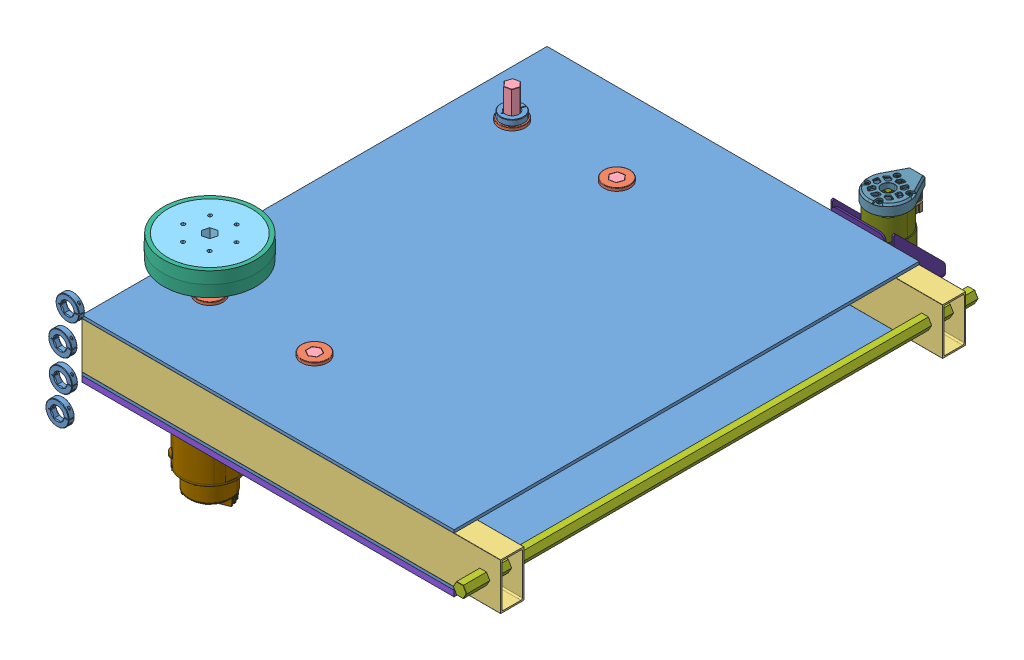
SolidWorks assembly ShooterAssem4, configuration Default. Lengths in mm.
Overall size (478.25 250.86 599.98).
87 component instances, 21 part files, 96 mates.
Components (placement in the parent):
- ShooterPlate-1: ShooterPlate [Default] at origin size (406.4 3.17 508)
- am-2986 FR8ZZ Hex Bearing.step-1: am-2986 FR8ZZ Hex Bearing.step [Default] at (50.8 6.4033 -88.9) x (0.268339 0 -0.963324) z (0 -1 0) size (31.12 31.12 7.93)
- am-2986 FR8ZZ Hex Bearing.step-2: am-2986 FR8ZZ Hex Bearing.step [Default] at (50.8 6.4033 -419.1) x (0.978513 0 -0.206187) z (0 -1 0) size (31.12 31.12 7.93)
- am-2986 FR8ZZ Hex Bearing.step-3: am-2986 FR8ZZ Hex Bearing.step [Default] at (165.1 6.4033 -419.1) x (0.331233 0 -0.943549) z (0 -1 0) size (31.12 31.12 7.93)
- am-2986 FR8ZZ Hex Bearing.step-4: am-2986 FR8ZZ Hex Bearing.step [Default] at (165.1 6.4033 -88.9) x (0.016765 0 0.999859) z (0 -1 0) size (31.12 31.12 7.93)
- side-4: side [Default] at (457.2 -25.4 -495.3) x (0 0 1) z (-1 0 0) size (25.4 50.8 457.2)
- side-5: side [Default] at (457.2 -25.4 -12.7) x (0 0 1) z (-1 0 0) size (25.4 50.8 457.2)
- 4in hex shaft-1: 4in hex shaft [Default] at (165.1 -95.1967 -88.9) x (0.874286 0 0.485411) z (0 1 0) size (14.66 12.7 101.6)
- 4in hex shaft-2: 4in hex shaft [Default] at (165.1 6.4033 -419.1) x (0.331233 0 -0.943549) z (0 -1 0) size (14.66 12.7 101.6)
- 4in hex shaft-3: 4in hex shaft [Default] at (50.8 39.1882 -88.9) x (0.268339 0 -0.963324) z (0 -1 0) size (14.66 12.7 101.6)
- 4in hex shaft-4: 4in hex shaft [Default] at (50.8 -64.1161 -419.1) x (0.978513 0 -0.206187) z (0 1 0) size (14.66 12.7 101.6)
- am-2647 4inWheel 500 Hex REV2-1: am-2647 4inWheel 500 Hex REV2 [Default] at (165.0712 -29.2956 -419.0946) x (0 -1 0) z (-0.331233 0 0.943549) size (25.4 101.6 101.6)
  - am-2647 4inWheel 500 Hex REV2.STEP-1: am-2647 4inWheel 500 Hex REV2.STEP [Default] at origin size (25.4 101.6 101.6)
    - 4in Wheel Intergreated Hub 500 HEX.STEP-1: 4in Wheel Intergreated Hub 500 HEX.STEP [Default] at origin size (25.4 92.71 92.71)
    - 4in Tread.STEP-1: 4in Tread.STEP [Default] at origin size (25.4 101.6 101.6)
- am-2647 4inWheel 500 Hex REV2-5: am-2647 4inWheel 500 Hex REV2 [Default] at (165.0739 -35.2807 -88.9436) x (0 -1 0) z (0.874286 0 0.485411) size (25.4 101.6 101.6)
  - am-2647 4inWheel 500 Hex REV2.STEP-1: am-2647 4inWheel 500 Hex REV2.STEP [Default] at origin size (25.4 101.6 101.6)
    - 4in Wheel Intergreated Hub 500 HEX.STEP-1: 4in Wheel Intergreated Hub 500 HEX.STEP [Default] at origin size (25.4 92.71 92.71)
    - 4in Tread.STEP-1: 4in Tread.STEP [Default] at origin size (25.4 101.6 101.6)
- am-2647 4inWheel 500 Hex REV2-6: am-2647 4inWheel 500 Hex REV2 [Default] at (50.7804 -22.6519 -419.1218) x (0 1 0) z (0.310693 0 -0.95051) size (25.4 101.6 101.6)
  - am-2647 4inWheel 500 Hex REV2.STEP-1: am-2647 4inWheel 500 Hex REV2.STEP [Default] at origin size (25.4 101.6 101.6)
    - 4in Wheel Intergreated Hub 500 HEX.STEP-1: 4in Wheel Intergreated Hub 500 HEX.STEP [Default] at origin size (25.4 92.71 92.71)
    - 4in Tread.STEP-1: 4in Tread.STEP [Default] at origin size (25.4 101.6 101.6)
- am-2647 4inWheel 500 Hex REV2-7: am-2647 4inWheel 500 Hex REV2 [Default] at (50.7921 47.535 -88.8717) x (0 -1 0) z (0.700094 0 0.714051) size (25.4 101.6 101.6)
  - am-2647 4inWheel 500 Hex REV2.STEP-1: am-2647 4inWheel 500 Hex REV2.STEP [Default] at origin size (25.4 101.6 101.6)
    - 4in Wheel Intergreated Hub 500 HEX.STEP-1: 4in Wheel Intergreated Hub 500 HEX.STEP [Default] at origin size (25.4 92.71 92.71)
    - 4in Tread.STEP-1: 4in Tread.STEP [Default] at origin size (25.4 101.6 101.6)
- am-2986 FR8ZZ Hex Bearing.step-5: am-2986 FR8ZZ Hex Bearing.step [Default] at (165.1 -57.2033 -88.9) x (0.874286 0 0.485411) z (0 1 0) size (31.12 31.12 7.93)
- am-2986 FR8ZZ Hex Bearing.step-7: am-2986 FR8ZZ Hex Bearing.step [Default] at (165.1 -57.2033 -419.1) x (-0.651521 0 -0.758631) z (0 1 0) size (31.12 31.12 7.93)
- am-2986 FR8ZZ Hex Bearing.step-8: am-2986 FR8ZZ Hex Bearing.step [Default] at (50.8 -57.2033 -419.1) x (0.667819 0 0.744323) z (0 1 0) size (31.12 31.12 7.93)
- am-2986 FR8ZZ Hex Bearing.step-9: am-2986 FR8ZZ Hex Bearing.step [Default] at (50.8 -47.5717 -88.9) x (-0.968433 0 0.249274) z (0 -1 0) size (31.12 31.12 7.93)
- ShooterPlate-2: ShooterPlate [Default] at (0 -53.975 0) size (406.4 3.17 508)
- shooteraxle-1: shooteraxle [Default] at (438.15 -25.4 -533.4) size (14.66 12.7 558.8)
- ThickStick-1: ThickStick [Default] at (0 -60.325 -482.6) size (406.4 6.35 25.4)
- ThickStick-2: ThickStick [Default] at (0 -60.325 0) size (406.4 6.35 25.4)
- Falcon 500.step-2: Falcon 500.step [Default] at (50.8431 -160.0533 -419.2317) x (0.853787 0 -0.520622) z (0 1 0) size (62.05 60 125.3)
- Falcon 500.step-3: Falcon 500.step [Default] at (50.7628 -158.349 -88.7665) x (-0.623742 0 0.78163) z (0 1 0) size (62.05 60 125.3)
- 775pro.step-1: 775pro.step [Default] at (339.185 -55.325 -541.274) x (-1 0 0) z (0 -1 0) size (44.99 55.15 90.45)
  - 217-6457-000 Rev2.step-1: 217-6457-000 Rev2.step [Default] at (0 0 -66.1) x (1 0 0) z (0 1 0) size (44.99 33.26 55.15)
    - 217-6457-900 Rev1.step-1: 217-6457-900 Rev1.step [Default] at (0 5.3622 0) x (-1 0 0.000693) z (0.000693 0 1) size (41.5 28.13 51.51)
      - 217-6457-901 Rev3_Instruction Config.step-1: 217-6457-901 Rev3_Instruction Config.step [Default] at origin size (41.5 2.36 51.5)
      - 30-45BBS Rev1_SHORTENED CONTACT.step-1: 30-45BBS Rev1_SHORTENED CONTACT.step [Default] at (3.95 14.4494 26.711) x (0 1 0) z (0 0 -1) size (26 3.6 2)
      - 30-45BBS Rev1_SHORTENED CONTACT.step-2: 30-45BBS Rev1_SHORTENED CONTACT.step [Default] at (-3.9748 14.4494 26.711) x (0 1 0) z (0 0 -1) size (26 3.6 2)
      - PA45XX-X Rev1.step-1: PA45XX-X Rev1.step [Default] at (-8.4198 2.3622 73.1531) x (0 1 0) z (-1 0 0) size (24.71 8.41 8.41)
      - PA45XX-X Rev1.step-2: PA45XX-X Rev1.step [Default] at (-0.495 2.3622 73.1531) x (0 1 0) z (-1 0 0) size (24.71 8.41 8.41)
    - 217-6457-001 Rev4.step-1: 217-6457-001 Rev4.step [Default] at origin size (41.49 7.8 41.49)
    - 217-6457-002 Rev7.step-1: 217-6457-002 Rev7.step [Default] at (0 0.05 0) size (44.99 11.5 55.15)
    - 217-9191-008 Rev1.step-1: 217-9191-008 Rev1.step [Default] at (81.4247 7.8 32.3804) x (-0.560945 0 -0.827853) z (0 1 0) size (4.2 4.2 11.81)
    - 217-9191-008 Rev1.step-2: 217-9191-008 Rev1.step [Default] at (32.3804 7.8 -81.4247) x (-0.827853 0 0.560945) z (0 1 0) size (4.2 4.2 11.81)
    - 217-9191-008 Rev1.step-3: 217-9191-008 Rev1.step [Default] at (-81.4247 7.8 -32.3804) x (0.560945 0 0.827853) z (0 1 0) size (4.2 4.2 11.81)
    - 217-9191-008 Rev1.step-4: 217-9191-008 Rev1.step [Default] at (-32.3804 7.8 81.4247) x (0.827853 0 -0.560945) z (0 1 0) size (4.2 4.2 11.81)
  - 217-4347-000 Rev2.step-1: 217-4347-000 Rev2.step [Default] x (0 0 -1) z (-1 0 0) size (88 44.3 44.3)
- 775 motor mount-5: 775 motor mount [Default] at (371.57 8.477 -513.08) x (1 0 0) z (0 1 0) size (68.77 61.47 68.8)
- ip-4187 Spline to 500 Hex.step-1: ip-4187 Spline to 500 Hex.step [Default] at (50.7628 -68.199 -88.7665) x (-0.700094 0 -0.714051) z (0 -1 0) size (14.66 12.7 25.4)
- ip-4187 Spline to 500 Hex.step-2: ip-4187 Spline to 500 Hex.step [Default] at (50.8431 -69.9033 -419.2317) x (0.310693 0 -0.95051) z (0 -1 0) size (14.66 12.7 25.4)
- Clamping Shaft Collar - 1_2 Hex ID (217-2737).step-1: Clamping Shaft Collar - 1_2 Hex ID (217-2737).step [Default] at (-0.997 -77.5069 22.879) size (25.39 25.4 6.35)
- Clamping Shaft Collar - 1_2 Hex ID (217-2737).step-2: Clamping Shaft Collar - 1_2 Hex ID (217-2737).step [Default] at (-3.2593 -49.7388 17.0471) size (25.39 25.4 6.35)
- Clamping Shaft Collar - 1_2 Hex ID (217-2737).step-3: Clamping Shaft Collar - 1_2 Hex ID (217-2737).step [Default] at (-3.3517 -15.0829 17.5296) size (25.39 25.4 6.35)
- Clamping Shaft Collar - 1_2 Hex ID (217-2737).step-4: Clamping Shaft Collar - 1_2 Hex ID (217-2737).step [Default] at (-3.7504 13.5033 9.0043) size (25.39 25.4 6.35)
- Clamping Shaft Collar - 1_2 Hex ID (217-2737).step-5: Clamping Shaft Collar - 1_2 Hex ID (217-2737).step [Default] at (50.8456 -46.101 -419.2394) x (-0.978513 0 0.206187) z (0 1 0) size (25.39 25.4 6.35)
- Clamping Shaft Collar - 1_2 Hex ID (217-2737).step-6: Clamping Shaft Collar - 1_2 Hex ID (217-2737).step [Default] at (50.8456 -39.751 -419.2394) x (0.667819 0 0.744323) z (0 -1 0) size (25.39 25.4 6.35)
- Clamping Shaft Collar - 1_2 Hex ID (217-2737).step-7: Clamping Shaft Collar - 1_2 Hex ID (217-2737).step [Default] at (50.9435 -8.001 -419.1302) x (-0.978513 0 0.206187) z (0 1 0) size (25.39 25.4 6.35)
- Clamping Shaft Collar - 1_2 Hex ID (217-2737).step-8: Clamping Shaft Collar - 1_2 Hex ID (217-2737).step [Default] at (50.8979 9.5783 -418.9908) x (0.310693 0 -0.95051) z (0 -1 0) size (25.39 25.4 6.35)
- 1_2 Hex Shaft Coupler (217-4008)-1: 1_2 Hex Shaft Coupler (217-4008) [Default] at (50.7814 -74.549 -88.8333) x (0.968433 0 -0.249274) z (0 1 0) size (25.76 22.32 38.1)
  - 1_2 Hex Shaft Coupler (217-4008).step-1: 1_2 Hex Shaft Coupler (217-4008).step [Default] at origin size (25.76 22.32 38.1)
    - 217-4008-001 Rev1.step-1: 217-4008-001 Rev1.step [Default] at origin size (25.38 10.66 38.1)
    - 217-4008-001 Rev1.step-2: 217-4008-001 Rev1.step [Default] x (1 0 0) z (0 0 -1) size (25.38 10.66 38.1)
    - 217-4008-002 Rev1_91251A108.step-1: 217-4008-002 Rev1_91251A108.step [Default] at (9.7928 7.025 4.7625) x (0.994016 0 -0.109231) z (0 1 0) size (4.65 4.65 12.38)
    - 217-4008-002 Rev1_91251A108.step-2: 217-4008-002 Rev1_91251A108.step [Default] at (9.7928 7.025 14.2875) x (-0.765668 0 -0.643235) z (0 1 0) size (4.65 4.65 12.38)
    - 217-4008-002 Rev1_91251A108.step-3: 217-4008-002 Rev1_91251A108.step [Default] at (-9.7928 7.025 14.2875) x (-0.114094 0 0.99347) z (0 1 0) size (4.65 4.65 12.38)
    - 217-4008-002 Rev1_91251A108.step-4: 217-4008-002 Rev1_91251A108.step [Default] at (-9.7928 7.025 4.7625) x (0.20346 0 0.979083) z (0 1 0) size (4.65 4.65 12.38)
    - 217-4008-002 Rev1_91251A108.step-5: 217-4008-002 Rev1_91251A108.step [Default] at (-9.7928 -7.025 -4.7625) x (0.20346 0 -0.979083) z (0 -1 0) size (4.65 4.65 12.38)
    - 217-4008-002 Rev1_91251A108.step-6: 217-4008-002 Rev1_91251A108.step [Default] at (-9.7928 -7.025 -14.2875) x (-0.114094 0 -0.99347) z (0 -1 0) size (4.65 4.65 12.38)
    - 217-4008-002 Rev1_91251A108.step-7: 217-4008-002 Rev1_91251A108.step [Default] at (9.7928 -7.025 -14.2875) x (-0.765668 0 0.643235) z (0 -1 0) size (4.65 4.65 12.38)
    - 217-4008-002 Rev1_91251A108.step-8: 217-4008-002 Rev1_91251A108.step [Default] at (9.7928 -7.025 -4.7625) x (0.994016 0 0.109231) z (0 -1 0) size (4.65 4.65 12.38)
- 1_2 Hex Shaft Coupler (217-4008)-2: 1_2 Hex Shaft Coupler (217-4008) [Default] at (50.8215 -76.2533 -419.1659) x (0.978513 0 -0.206187) z (0 -1 0) size (25.76 22.32 38.1)
  - 1_2 Hex Shaft Coupler (217-4008).step-1: 1_2 Hex Shaft Coupler (217-4008).step [Default] at origin size (25.76 22.32 38.1)
    - 217-4008-001 Rev1.step-1: 217-4008-001 Rev1.step [Default] at origin size (25.38 10.66 38.1)
    - 217-4008-001 Rev1.step-2: 217-4008-001 Rev1.step [Default] x (1 0 0) z (0 0 -1) size (25.38 10.66 38.1)
    - 217-4008-002 Rev1_91251A108.step-1: 217-4008-002 Rev1_91251A108.step [Default] at (9.7928 7.025 4.7625) x (0.994016 0 -0.109231) z (0 1 0) size (4.65 4.65 12.38)
    - 217-4008-002 Rev1_91251A108.step-2: 217-4008-002 Rev1_91251A108.step [Default] at (9.7928 7.025 14.2875) x (-0.765668 0 -0.643235) z (0 1 0) size (4.65 4.65 12.38)
    - 217-4008-002 Rev1_91251A108.step-3: 217-4008-002 Rev1_91251A108.step [Default] at (-9.7928 7.025 14.2875) x (-0.114094 0 0.99347) z (0 1 0) size (4.65 4.65 12.38)
    - 217-4008-002 Rev1_91251A108.step-4: 217-4008-002 Rev1_91251A108.step [Default] at (-9.7928 7.025 4.7625) x (0.20346 0 0.979083) z (0 1 0) size (4.65 4.65 12.38)
    - 217-4008-002 Rev1_91251A108.step-5: 217-4008-002 Rev1_91251A108.step [Default] at (-9.7928 -7.025 -4.7625) x (0.20346 0 -0.979083) z (0 -1 0) size (4.65 4.65 12.38)
    - 217-4008-002 Rev1_91251A108.step-6: 217-4008-002 Rev1_91251A108.step [Default] at (-9.7928 -7.025 -14.2875) x (-0.114094 0 -0.99347) z (0 -1 0) size (4.65 4.65 12.38)
    - 217-4008-002 Rev1_91251A108.step-7: 217-4008-002 Rev1_91251A108.step [Default] at (9.7928 -7.025 -14.2875) x (-0.765668 0 0.643235) z (0 -1 0) size (4.65 4.65 12.38)
    - 217-4008-002 Rev1_91251A108.step-8: 217-4008-002 Rev1_91251A108.step [Default] at (9.7928 -7.025 -4.7625) x (0.994016 0 0.109231) z (0 -1 0) size (4.65 4.65 12.38)
Mates (geometry in assembly coordinates):
- Coincident23: coincident aligned: plane of ShooterPlate-1 through (0 3.175 -508) normal (0 0 -1); plane of side-4 through (0 -50.546 -508) normal (0 0 -1)
- Coincident24: coincident anti-aligned: plane of ShooterPlate-1 through (0 0 0) normal (0 -1 0); plane of side-4 through (0 0 -507.746) normal (0 1 0)
- Coincident25: coincident aligned: plane of ShooterPlate-1 through (0 3.175 0) normal (-1 0 0); plane of side-4 through (0 -0.254 -482.854) normal (-1 0 0)
- Coincident26: coincident anti-aligned: plane of ShooterPlate-1 through (0 0 0) normal (0 -1 0); plane of side-5 through (0 0 -25.146) normal (0 1 0)
- Coincident28: coincident aligned: plane of ShooterPlate-1 through (0 3.175 0) normal (0 0 1); plane of side-5 through (0 -0.254 0) normal (0 0 1)
- Coincident29: coincident aligned: plane of ShooterPlate-1 through (0 3.175 0) normal (-1 0 0); plane of side-5 through (0 -0.254 -0.254) normal (-1 0 0)
- Concentric1: concentric aligned: cylinder of ShooterPlate-1 through (165.1 0 -419.1) axis (0 1 0) radius 14.2875; cylinder of am-2986 FR8ZZ Hex Bearing.step-3 through (165.1 -1.524 -419.1) axis (0 1 0) radius 14.2875
- Coincident33: coincident anti-aligned: plane of ShooterPlate-1 through (0 0 0) normal (0 -1 0); plane of am-2986 FR8ZZ Hex Bearing.step-3 through (169.7273 0 -432.2814) normal (0 1 0)
- Concentric3: concentric aligned: cylinder of ShooterPlate-1 through (165.1 0 -88.9) axis (0 1 0) radius 14.2875; cylinder of am-2986 FR8ZZ Hex Bearing.step-4 through (165.1 -1.524 -88.9) axis (0 1 0) radius 14.2875
- Coincident35: coincident anti-aligned: plane of ShooterPlate-1 through (0 0 0) normal (0 -1 0); plane of am-2986 FR8ZZ Hex Bearing.step-4 through (165.3342 0 -74.932) normal (0 1 0)
- Concentric4: concentric aligned: cylinder of ShooterPlate-1 through (50.8 0 -88.9) axis (0 1 0) radius 14.2875; cylinder of am-2986 FR8ZZ Hex Bearing.step-1 through (50.8 -1.524 -88.9) axis (0 1 0) radius 14.2875
- Coincident36: coincident anti-aligned: plane of ShooterPlate-1 through (0 0 0) normal (0 -1 0); plane of am-2986 FR8ZZ Hex Bearing.step-1 through (54.5487 0 -102.3576) normal (0 1 0)
- Coincident38: coincident anti-aligned: plane of am-2986 FR8ZZ Hex Bearing.step-3 through (162.6713 -1.524 -412.1816) normal (-0.184918 0 -0.982754); plane of 4in hex shaft-2 through (162.6713 -95.1967 -412.1816) normal (0.184918 0 0.982754)
- Coincident41: coincident aligned: plane of am-2986 FR8ZZ Hex Bearing.step-3 through (165.1 6.4033 -419.1) normal (0 1 0); plane of 4in hex shaft-2 through (165.1 6.4033 -419.1) normal (0 1 0)
- Coincident42: coincident anti-aligned: plane of am-2986 FR8ZZ Hex Bearing.step-3 through (157.8941 -1.524 -417.7441) normal (0.758631 0 -0.651521); plane of 4in hex shaft-2 through (157.8941 -95.1967 -417.7441) normal (-0.758631 0 0.651521)
- Coincident43: coincident aligned: plane of am-2986 FR8ZZ Hex Bearing.step-4 through (165.1 6.4033 -88.9) normal (0 1 0); plane of 4in hex shaft-1 through (165.1 6.4033 -88.9) normal (0 1 0)
- Coincident44: coincident anti-aligned: plane of am-2986 FR8ZZ Hex Bearing.step-4 through (158.6894 -1.524 -92.4592) normal (0.999859 0 -0.016765); plane of 4in hex shaft-1 through (158.8124 6.4033 -85.1279) normal (-0.999859 0 0.016765)
- Coincident45: coincident anti-aligned: plane of am-2986 FR8ZZ Hex Bearing.step-4 through (171.3876 -1.524 -92.6721) normal (-0.485411 0 0.874286); plane of 4in hex shaft-1 through (164.9771 6.4033 -96.2313) normal (0.485411 0 -0.874286)
- Coincident47: coincident anti-aligned: plane of am-2986 FR8ZZ Hex Bearing.step-2 through (45.9033 -1.524 -424.5576) normal (0.95051 0 0.310693); plane of 4in hex shaft-4 through (43.6252 37.4839 -417.5882) normal (-0.95051 0 -0.310693)
- Coincident48: coincident anti-aligned: plane of am-2986 FR8ZZ Hex Bearing.step-2 through (53.0781 -1.524 -426.0695) normal (0.206187 0 0.978513); plane of 4in hex shaft-4 through (45.9033 37.4839 -424.5576) normal (-0.206187 0 -0.978513)
- Coincident51: coincident anti-aligned: plane of am-2986 FR8ZZ Hex Bearing.step-1 through (55.9333 -1.524 -83.6643) normal (-0.963324 0 -0.268339); plane of 4in hex shaft-3 through (55.9333 -62.4118 -83.6643) normal (0.963324 0 0.268339)
- Coincident52: coincident anti-aligned: plane of am-2986 FR8ZZ Hex Bearing.step-1 through (48.8324 -1.524 -81.8366) normal (-0.249274 0 -0.968433); plane of 4in hex shaft-3 through (48.8324 -62.4118 -81.8366) normal (0.249274 0 0.968433)
- Coincident55: coincident anti-aligned: plane of 4in hex shaft-4 through (55.6967 37.4839 -413.6424) normal (0.206187 0 0.978513); plane of am-2647 4inWheel 500 Hex REV2-6/am-2647 4inWheel 500 Hex REV2.STEP-1/4in Wheel Intergreated Hub 500 HEX.STEP-1 through (48.4932 -36.576 -412.1245) normal (-0.206187 0 -0.978513)
- Coincident56: coincident anti-aligned: plane of 4in hex shaft-4 through (57.9748 37.4839 -420.6118) normal (0.95051 0 0.310693); plane of am-2647 4inWheel 500 Hex REV2-6/am-2647 4inWheel 500 Hex REV2.STEP-1/4in Wheel Intergreated Hub 500 HEX.STEP-1 through (55.6967 -36.576 -413.6424) normal (-0.95051 0 -0.310693)
- Coincident57: coincident anti-aligned: plane of 4in hex shaft-3 through (52.7676 -62.4118 -95.9634) normal (-0.249274 0 -0.968433); plane of am-2647 4inWheel 500 Hex REV2-7/am-2647 4inWheel 500 Hex REV2.STEP-1/4in Wheel Intergreated Hub 500 HEX.STEP-1 through (45.6383 61.4591 -94.1284) normal (0.249274 0 0.968433)
- Coincident60: coincident anti-aligned: plane of 4in hex shaft-3 through (57.9009 -62.4118 -90.7278) normal (0.714051 0 -0.700094); plane of am-2647 4inWheel 500 Hex REV2-7/am-2647 4inWheel 500 Hex REV2.STEP-1/4in Wheel Intergreated Hub 500 HEX.STEP-1 through (52.7676 61.4591 -95.9634) normal (-0.714051 0 0.700094)
- Coincident66: coincident anti-aligned: plane of 4in hex shaft-1 through (165.2229 6.4033 -81.5687) normal (-0.485411 0 0.874286); plane of am-2647 4inWheel 500 Hex REV2-5/am-2647 4inWheel 500 Hex REV2.STEP-1/4in Wheel Intergreated Hub 500 HEX.STEP-1 through (165.1973 -21.3567 -81.5829) normal (0.485411 0 -0.874286)
- Coincident67: coincident anti-aligned: plane of 4in hex shaft-1 through (171.3876 6.4033 -92.6721) normal (0.999859 0 -0.016765); plane of am-2647 4inWheel 500 Hex REV2-5/am-2647 4inWheel 500 Hex REV2.STEP-1/4in Wheel Intergreated Hub 500 HEX.STEP-1 through (171.3867 -21.3567 -92.7308) normal (-0.999859 0 0.016765)
- Coincident70: coincident anti-aligned: plane of 4in hex shaft-2 through (172.3059 -95.1967 -420.4559) normal (0.758631 0 -0.651521); plane of am-2647 4inWheel 500 Hex REV2-1/am-2647 4inWheel 500 Hex REV2.STEP-1/4in Wheel Intergreated Hub 500 HEX.STEP-1 through (167.5096 -15.3716 -426.0407) normal (-0.758631 0 0.651521)
- Coincident71: coincident anti-aligned: plane of 4in hex shaft-2 through (169.8772 -95.1967 -413.5375) normal (0.943549 0 0.331233); plane of am-2647 4inWheel 500 Hex REV2-1/am-2647 4inWheel 500 Hex REV2.STEP-1/4in Wheel Intergreated Hub 500 HEX.STEP-1 through (172.3059 -15.3716 -420.4559) normal (-0.943549 0 -0.331233)
- Coincident73: coincident anti-aligned: plane of 4in hex shaft-1 through (171.3876 6.4033 -92.6721) normal (0.999859 0 -0.016765); plane of am-2986 FR8ZZ Hex Bearing.step-5 through (171.3876 -49.276 -92.6721) normal (-0.999859 0 0.016765)
- Coincident74: coincident anti-aligned: plane of 4in hex shaft-1 through (158.6894 6.4033 -92.4592) normal (-0.514449 0 -0.857521); plane of am-2986 FR8ZZ Hex Bearing.step-5 through (158.6894 -49.276 -92.4592) normal (0.514449 0 0.857521)
- Coincident87: coincident anti-aligned: plane of side-5 through (0 -50.8 -0.254) normal (0 -1 0); plane of ShooterPlate-2 through (0 -50.8 0) normal (0 1 0)
- Coincident88: coincident aligned: plane of side-5 through (0 -0.254 -0.254) normal (-1 0 0); plane of ShooterPlate-2 through (0 -50.8 0) normal (-1 0 0)
- Coincident91: coincident anti-aligned: plane of am-2986 FR8ZZ Hex Bearing.step-5 through (177.3138 -50.8 -82.1188) normal (0 -1 0); plane of ShooterPlate-2 through (0 -50.8 0) normal (0 1 0)
- Coincident92: coincident anti-aligned: plane of am-2986 FR8ZZ Hex Bearing.step-8 through (60.1294 -50.8 -408.7018) normal (0 -1 0); plane of ShooterPlate-2 through (0 -50.8 0) normal (0 1 0)
- Coincident93: coincident anti-aligned: plane of 4in hex shaft-4 through (53.0781 37.4839 -426.0695) normal (0.744323 0 -0.667819); plane of am-2986 FR8ZZ Hex Bearing.step-8 through (53.0781 -49.276 -426.0695) normal (-0.744323 0 0.667819)
- Coincident94: coincident anti-aligned: plane of 4in hex shaft-4 through (45.9033 37.4839 -424.5576) normal (-0.206187 0 -0.978513); plane of am-2986 FR8ZZ Hex Bearing.step-8 through (45.9033 -49.276 -424.5576) normal (0.206187 0 0.978513)
- Coincident96: coincident anti-aligned: plane of 4in hex shaft-2 through (167.5287 -95.1967 -426.0184) normal (-0.184918 0 -0.982754); plane of am-2986 FR8ZZ Hex Bearing.step-7 through (160.3228 -49.276 -424.6625) normal (0.184918 0 0.982754)
- Coincident97: coincident anti-aligned: plane of 4in hex shaft-2 through (160.3228 -95.1967 -424.6625) normal (-0.943549 0 -0.331233); plane of am-2986 FR8ZZ Hex Bearing.step-7 through (157.8941 -49.276 -417.7441) normal (0.943549 0 0.331233)
- Coincident98: coincident anti-aligned: plane of am-2986 FR8ZZ Hex Bearing.step-7 through (155.9983 -50.8 -429.6981) normal (0 -1 0); plane of ShooterPlate-2 through (0 -50.8 0) normal (0 1 0)
- Coincident100: coincident anti-aligned: plane of side-4 through (434.4838 -31.75 -482.6) normal (0.866025 0.5 0); plane of shooteraxle-1 through (434.4838 -31.75 25.4) normal (-0.866025 -0.5 0)
- Coincident101: coincident anti-aligned: plane of side-4 through (441.8162 -31.75 -482.6) normal (0 1 0); plane of shooteraxle-1 through (441.8162 -31.75 25.4) normal (0 -1 0)
- Distance1: distance = 25.4 mm aligned: plane of side-4 through (0 -50.546 -508) normal (0 0 -1); plane of shooteraxle-1 through (438.15 -25.4 -533.4) normal (0 0 -1)
- Coincident103: coincident anti-aligned: plane of ShooterPlate-2 through (0 -53.975 0) normal (0 -1 0); plane of ThickStick-1 through (0 -53.975 -482.6) normal (0 1 0)
- Coincident104: coincident aligned: plane of ShooterPlate-2 through (406.4 -50.8 0) normal (1 0 0); plane of ThickStick-1 through (406.4 -53.975 -482.6) normal (1 0 0)
- Coincident105: coincident aligned: plane of ShooterPlate-2 through (0 -50.8 -508) normal (0 0 -1); plane of ThickStick-1 through (0 -53.975 -508) normal (0 0 -1)
- Coincident106: coincident anti-aligned: plane of ShooterPlate-2 through (0 -53.975 0) normal (0 -1 0); plane of ThickStick-2 through (0 -53.975 0) normal (0 1 0)
- Coincident107: coincident aligned: plane of ShooterPlate-2 through (406.4 -50.8 0) normal (1 0 0); plane of ThickStick-2 through (406.4 -53.975 0) normal (1 0 0)
- Coincident108: coincident aligned: plane of ShooterPlate-2 through (0 -50.8 0) normal (0 0 1); plane of ThickStick-2 through (0 -53.975 0) normal (0 0 1)
- Coincident116: coincident aligned: plane of side-4 through (0 -50.546 -508) normal (0 0 -1); plane of ShooterPlate-2 through (0 -50.8 -508) normal (0 0 -1)
- Coincident132: coincident anti-aligned: plane of side-5 through (0 -0.254 0) normal (0 0 1); plane of 775 motor mount-4 through (191.75 8.477 0) normal (0 0 -1)
- Coincident133: coincident aligned: plane of ThickStick-2 through (0 -60.325 0) normal (0 -1 0); plane of 775 motor mount-4 through (191.75 -60.325 61.468) normal (0 -1 0)
- Coincident135: coincident anti-aligned: plane of side-4 through (0 -50.546 -508) normal (0 0 -1); plane of 775 motor mount-5 through (371.57 8.477 -508) normal (0 0 1)
- Coincident136: coincident aligned: plane of ThickStick-1 through (0 -60.325 -482.6) normal (0 -1 0); plane of 775 motor mount-5 through (371.57 -60.325 -569.468) normal (0 -1 0)
- Coincident137: coincident aligned: plane of 775pro.step-1/217-4347-000 Rev2.step-1 through (339.185 -60.325 -538.774) normal (0 -1 0); circle of 775 motor mount-5
- Concentric9: concentric aligned: cylinder of 775pro.step-1/217-4347-000 Rev2.step-1 through (339.185 -55.325 -541.274) axis (0 -1 0) radius 8.75; cylinder of 775 motor mount-5 through (339.185 8.477 -541.274) axis (0 -1 0) radius 8.89
- Coincident138: coincident anti-aligned: plane of Falcon 500.step-3 through (48.5726 -93.599 -94.3525) normal (0 1 0); plane of ip-4187 Spline to 500 Hex.step-1 through (50.7628 -93.599 -88.7665) normal (0 -1 0)
- Concentric10: concentric anti-aligned: circle of Falcon 500.step-3; circle of ip-4187 Spline to 500 Hex.step-1
- Coincident139: coincident anti-aligned: plane of Falcon 500.step-2 through (50.9869 -95.3033 -413.2334) normal (0 1 0); plane of ip-4187 Spline to 500 Hex.step-2 through (50.8431 -95.3033 -419.2317) normal (0 -1 0)
- Concentric11: concentric anti-aligned: circle of Falcon 500.step-2; circle of ip-4187 Spline to 500 Hex.step-2
- Distance6: distance = 304.8 mm aligned: plane of 775 motor mount-5 through (304.8 -58.325 -569.468) normal (-1 0 0); plane of side-4 through (0 -0.254 -482.854) normal (-1 0 0)
- Concentric13: concentric aligned: cylinder of am-2986 FR8ZZ Hex Bearing.step-2 through (50.8 -1.524 -419.1) axis (0 1 0) radius 14.2875; cylinder of ShooterPlate-1 through (50.8 0 -419.1) axis (0 1 0) radius 14.2875
- Coincident169: coincident anti-aligned: plane of ShooterPlate-1 through (0 0 0) normal (0 -1 0); plane of am-2986 FR8ZZ Hex Bearing.step-2 through (64.4698 0 -421.9804) normal (0 1 0)
- Coincident170: coordinate: point of ShooterPlate-1
- Coincident171: coincident anti-aligned: plane of 4in hex shaft-4 through (48.5219 37.4839 -412.1305) normal (-0.744323 0 0.667819); plane of Clamping Shaft Collar - 1_2 Hex ID (217-2737).step-5 through (43.5273 -49.276 -417.6973) normal (0.744323 0 -0.667819)
- Coincident172: coincident anti-aligned: plane of 4in hex shaft-4 through (55.6967 37.4839 -413.6424) normal (0.206187 0 0.978513); plane of Clamping Shaft Collar - 1_2 Hex ID (217-2737).step-5 through (48.5219 -49.276 -412.1305) normal (-0.206187 0 -0.978513)
- Coincident173: coincident anti-aligned: plane of am-2986 FR8ZZ Hex Bearing.step-8 through (61.1896 -49.276 -407.5202) normal (0 1 0); plane of Clamping Shaft Collar - 1_2 Hex ID (217-2737).step-5 through (50.8456 -49.276 -419.2394) normal (0 -1 0)
- Coincident174: coincident anti-aligned: plane of 4in hex shaft-4 through (55.6967 37.4839 -413.6424) normal (0.206187 0 0.978513); plane of Clamping Shaft Collar - 1_2 Hex ID (217-2737).step-6 through (55.8402 -36.576 -413.6726) normal (-0.206187 0 -0.978513)
- Coincident175: coincident anti-aligned: plane of 4in hex shaft-4 through (48.5219 37.4839 -412.1305) normal (-0.744323 0 0.667819); plane of Clamping Shaft Collar - 1_2 Hex ID (217-2737).step-6 through (48.5219 -36.576 -412.1305) normal (0.744323 0 -0.667819)
- Coincident176: coincident anti-aligned: plane of am-2647 4inWheel 500 Hex REV2-6/am-2647 4inWheel 500 Hex REV2.STEP-1/4in Wheel Intergreated Hub 500 HEX.STEP-1 through (56.8162 -36.576 -417.1489) normal (0 -1 0); plane of Clamping Shaft Collar - 1_2 Hex ID (217-2737).step-6 through (50.8456 -36.576 -419.2394) normal (0 1 0)
- Coincident177: coincident anti-aligned: plane of 4in hex shaft-4 through (43.6252 37.4839 -417.5882) normal (-0.95051 0 -0.310693); plane of Clamping Shaft Collar - 1_2 Hex ID (217-2737).step-7 through (45.9489 -11.176 -424.697) normal (0.95051 0 0.310693)
- Coincident179: coincident anti-aligned: plane of 4in hex shaft-4 through (48.5219 37.4839 -412.1305) normal (-0.744323 0 0.667819); plane of Clamping Shaft Collar - 1_2 Hex ID (217-2737).step-7 through (43.6252 -11.176 -417.5882) normal (0.744323 0 -0.667819)
- Coincident180: coincident anti-aligned: plane of am-2647 4inWheel 500 Hex REV2-6/am-2647 4inWheel 500 Hex REV2.STEP-1/4in Wheel Intergreated Hub 500 HEX.STEP-1 through (56.8162 -11.176 -417.1489) normal (0 1 0); plane of Clamping Shaft Collar - 1_2 Hex ID (217-2737).step-7 through (50.9435 -11.176 -419.1302) normal (0 -1 0)
- Coincident181: coincident anti-aligned: plane of 4in hex shaft-4 through (45.9033 37.4839 -424.5576) normal (-0.206187 0 -0.978513); plane of Clamping Shaft Collar - 1_2 Hex ID (217-2737).step-8 through (45.9033 12.7533 -424.5576) normal (0.206187 0 0.978513)
- Coincident182: coincident anti-aligned: plane of 4in hex shaft-4 through (43.6252 37.4839 -417.5882) normal (-0.95051 0 -0.310693); plane of Clamping Shaft Collar - 1_2 Hex ID (217-2737).step-8 through (43.5796 12.7533 -417.4488) normal (0.95051 0 0.310693)
- Coincident183: coincident anti-aligned: plane of am-2986 FR8ZZ Hex Bearing.step-2 through (50.8 6.4033 -419.1) normal (0 1 0); plane of Clamping Shaft Collar - 1_2 Hex ID (217-2737).step-8 through (50.8979 6.4033 -418.9908) normal (0 -1 0)
- Coincident184: coincident anti-aligned: plane of 4in hex shaft-3 through (52.7676 -62.4118 -95.9634) normal (-0.249274 0 -0.968433); plane of 1_2 Hex Shaft Coupler (217-4008)-1/1_2 Hex Shaft Coupler (217-4008).step-1/217-4008-001 Rev1.step-1 through (52.7676 -93.599 -95.9634) normal (0.249274 0 0.968433)
- Coincident185: coincident anti-aligned: plane of 4in hex shaft-3 through (57.9009 -62.4118 -90.7278) normal (0.714051 0 -0.700094); plane of 1_2 Hex Shaft Coupler (217-4008)-1/1_2 Hex Shaft Coupler (217-4008).step-1/217-4008-001 Rev1.step-1 through (57.9494 -93.599 -90.6783) normal (-0.714051 0 0.700094)
- Coincident187: coincident anti-aligned: plane of 4in hex shaft-4 through (55.6967 37.4839 -413.6424) normal (0.206187 0 0.978513); plane of 1_2 Hex Shaft Coupler (217-4008)-2/1_2 Hex Shaft Coupler (217-4008).step-1/217-4008-001 Rev1.step-1 through (55.7645 -57.2033 -413.6566) normal (-0.206187 0 -0.978513)
- Coincident188: coincident anti-aligned: plane of 4in hex shaft-4 through (48.5219 37.4839 -412.1305) normal (-0.744323 0 0.667819); plane of 1_2 Hex Shaft Coupler (217-4008)-2/1_2 Hex Shaft Coupler (217-4008).step-1/217-4008-001 Rev1.step-1 through (48.5219 -57.2033 -412.1305) normal (0.744323 0 -0.667819)
- Coincident189: coincident anti-aligned: plane of am-2986 FR8ZZ Hex Bearing.step-8 through (50.8 -57.2033 -419.1) normal (0 -1 0); plane of 1_2 Hex Shaft Coupler (217-4008)-2/1_2 Hex Shaft Coupler (217-4008).step-1/217-4008-001 Rev1.step-1 through (50.8215 -57.2033 -419.1659) normal (0 1 0)
- Coincident190: coincident anti-aligned: plane of ip-4187 Spline to 500 Hex.step-2 through (45.9464 -95.3033 -424.6893) normal (-0.206187 0 -0.978513); plane of 1_2 Hex Shaft Coupler (217-4008)-2/1_2 Hex Shaft Coupler (217-4008).step-1/217-4008-001 Rev1.step-2 through (53.1212 -95.3033 -426.2012) normal (0.206187 0 0.978513)
- Coincident191: coincident anti-aligned: plane of ip-4187 Spline to 500 Hex.step-2 through (53.1212 -95.3033 -426.2012) normal (0.744323 0 -0.667819); plane of 1_2 Hex Shaft Coupler (217-4008)-2/1_2 Hex Shaft Coupler (217-4008).step-1/217-4008-001 Rev1.step-2 through (58.0641 -95.3033 -420.692) normal (-0.744323 0 0.667819)
- Coincident192: coincident anti-aligned: plane of Falcon 500.step-2 through (50.9869 -95.3033 -413.2334) normal (0 1 0); plane of 1_2 Hex Shaft Coupler (217-4008)-2/1_2 Hex Shaft Coupler (217-4008).step-1/217-4008-001 Rev1.step-2 through (50.8215 -95.3033 -419.1659) normal (0 -1 0)
- Coincident193: coincident anti-aligned: plane of 4in hex shaft-4 through (50.8 -64.1161 -419.1) normal (0 -1 0); plane of Falcon 500.step-2 through (51.2168 -64.1161 -422.191) normal (0 1 0)
- Coincident194: coincident anti-aligned: plane of Clamping Shaft Collar - 1_2 Hex ID (217-2737).step-5 through (50.8456 -42.926 -419.2394) normal (0 1 0); plane of Clamping Shaft Collar - 1_2 Hex ID (217-2737).step-6 through (50.8456 -42.926 -419.2394) normal (0 -1 0)
- Coincident195: coincident anti-aligned: plane of ip-4187 Spline to 500 Hex.step-1 through (48.7953 -93.599 -81.7031) normal (-0.714051 0 0.700094); plane of 1_2 Hex Shaft Coupler (217-4008)-1/1_2 Hex Shaft Coupler (217-4008).step-1/217-4008-001 Rev1.step-2 through (48.7953 -55.499 -81.7031) normal (0.714051 0 -0.700094)
- Coincident196: coincident anti-aligned: plane of ip-4187 Spline to 500 Hex.step-1 through (55.8962 -93.599 -83.5308) normal (0.249274 0 0.968433); plane of 1_2 Hex Shaft Coupler (217-4008)-1/1_2 Hex Shaft Coupler (217-4008).step-1/217-4008-001 Rev1.step-2 through (55.9632 -55.499 -83.5481) normal (-0.249274 0 -0.968433)
- Coincident197: coincident anti-aligned: plane of Falcon 500.step-3 through (48.5726 -93.599 -94.3525) normal (0 1 0); plane of 1_2 Hex Shaft Coupler (217-4008)-1/1_2 Hex Shaft Coupler (217-4008).step-1/217-4008-001 Rev1.step-1 through (50.7814 -93.599 -88.8333) normal (0 -1 0)
- Coincident198: coincident anti-aligned: plane of 4in hex shaft-3 through (50.8 -62.4118 -88.9) normal (0 -1 0); plane of Falcon 500.step-3 through (51.4256 -62.4118 -85.8583) normal (0 1 0)
- Coincident199: coincident anti-aligned: plane of am-2986 FR8ZZ Hex Bearing.step-9 through (37.271 -53.975 -85.4176) normal (0 1 0); plane of ShooterPlate-2 through (0 -53.975 0) normal (0 -1 0)
- Concentric14: concentric aligned: cylinder of am-2986 FR8ZZ Hex Bearing.step-9 through (50.8 -55.499 -88.9) axis (0 1 0) radius 14.2875; cylinder of ShooterPlate-2 through (50.8 -53.975 -88.9) axis (0 1 0) radius 14.2875
- Coincident201: coincident anti-aligned: plane of 4in hex shaft-3 through (43.6991 -62.4118 -87.0722) normal (-0.714051 0 0.700094); plane of am-2986 FR8ZZ Hex Bearing.step-9 through (43.6991 -55.499 -87.0722) normal (0.714051 0 -0.700094)
- Coincident202: coincident anti-aligned: plane of 4in hex shaft-3 through (48.8324 -62.4118 -81.8366) normal (0.249274 0 0.968433); plane of am-2986 FR8ZZ Hex Bearing.step-9 through (48.8324 -55.499 -81.8366) normal (-0.249274 0 -0.968433)
- Coincident203: coincident anti-aligned: plane of am-2986 FR8ZZ Hex Bearing.step-9 through (35.7336 -55.499 -85.0219) normal (0 -1 0); plane of 1_2 Hex Shaft Coupler (217-4008)-1/1_2 Hex Shaft Coupler (217-4008).step-1/217-4008-001 Rev1.step-2 through (50.7814 -55.499 -88.8333) normal (0 1 0)
